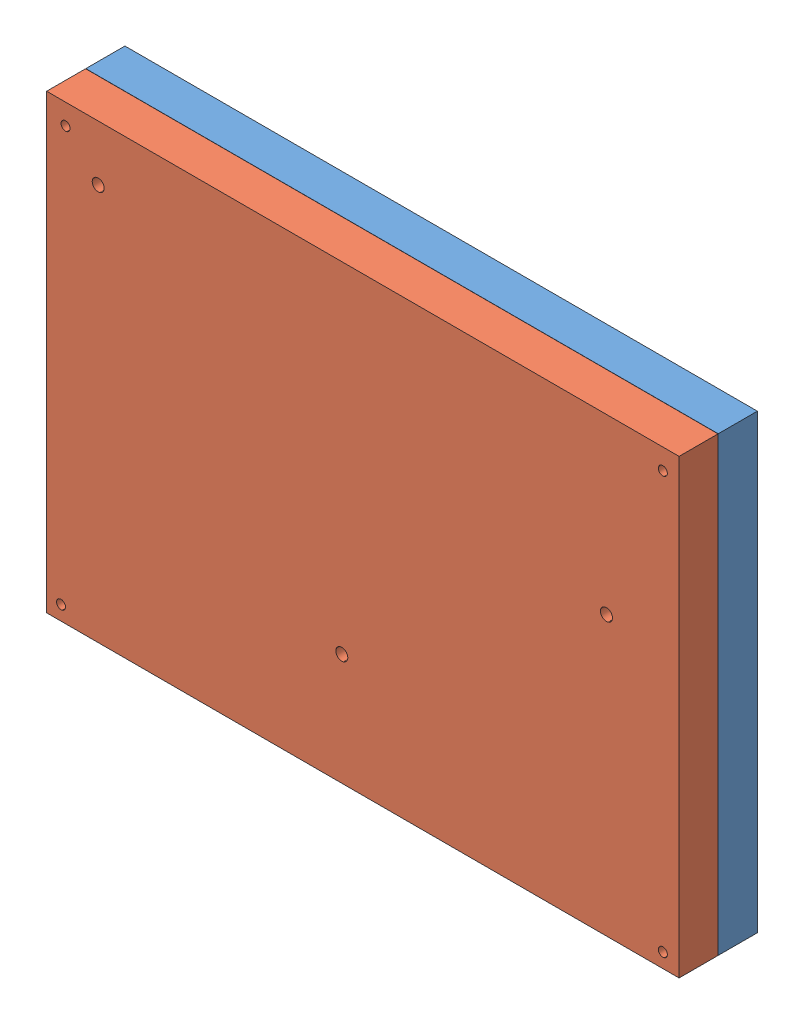
SolidWorks assembly moule1, configuration Défaut. Lengths in mm.
Overall size (210 150 26).
3 component instances, 3 part files, 3 mates.
Components (placement in the parent):
- mousse-1: mousse [Défaut] at (-233.0223 99.9205 182.5) size (190 130 15) (hidden)
- mouleinfinjection-1: mouleinfinjection [Défaut] at (-4.099 -3.8613 178.5255) size (210 150 13)
- moulesupinjection-1: moulesupinjection [Défaut] at (-4.099 -3.8613 191.5255) size (210 150 13)
Mates (geometry in assembly coordinates):
- Coïncidente1: coincident anti-aligned: plane of mouleinfinjection-1 through (-4.099 -3.8613 191.5255) normal (0 0 1); plane of moulesupinjection-1 through (-4.099 -3.8613 191.5255) normal (0 0 -1)
- Coïncidente2: coincident aligned: plane of mouleinfinjection-1 through (-109.099 -78.8613 191.5255) normal (0 -1 0); plane of moulesupinjection-1 through (-109.099 -78.8613 204.5255) normal (0 -1 0)
- Coïncidente3: coincident aligned: plane of mouleinfinjection-1 through (-109.099 -78.8613 191.5255) normal (-1 0 0); plane of moulesupinjection-1 through (-109.099 -78.8613 204.5255) normal (-1 0 0)
